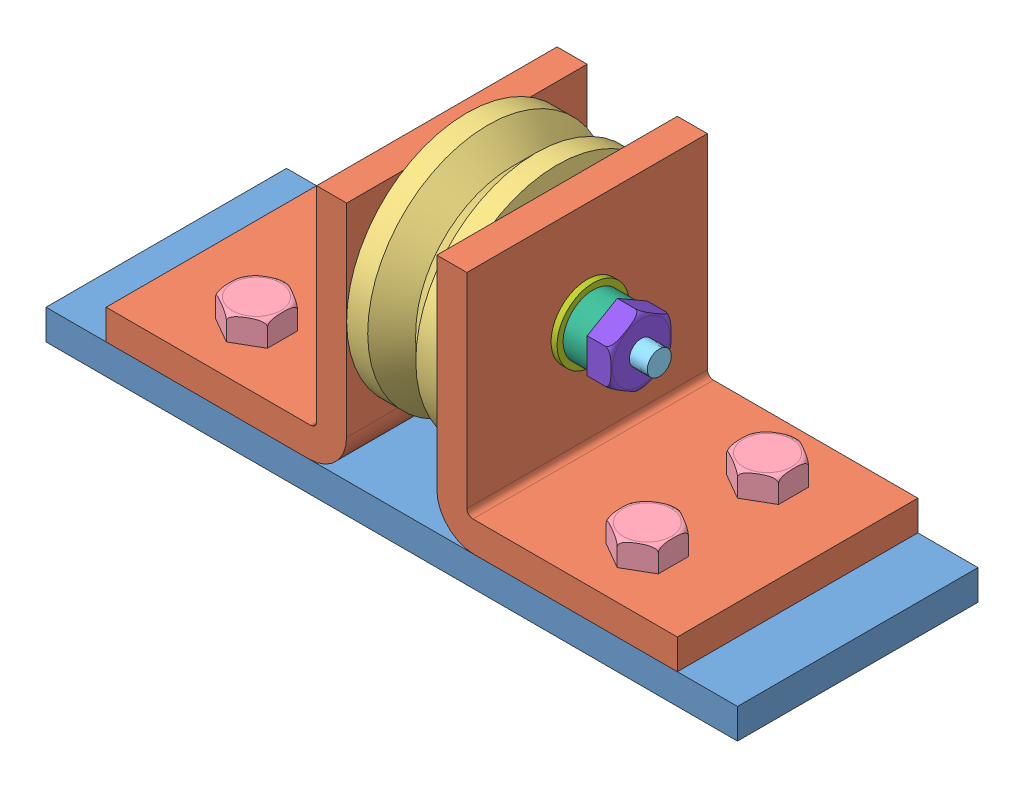
SolidWorks assembly Assem1, configuration Default. Lengths in mm.
Overall size (115 53.85 51.69).
12 component instances, 8 part files, 29 mates.
Components (placement in the parent):
- Part1-1: Part1 [Default] at (31.9592 57.592 95.7045) size (115 5 40)
- Part2-1: Part2 [Default] at (59.4592 62.592 95.7045) size (40 40 40)
- Part3-1: Part3 [Default] at (31.9592 83.092 95.7045) x (1 0 0) z (0 0.358901 -0.933376) size (15 40 40)
- Part8-1: Part8 [Default] at (64.4592 62.592 105.7045) x (-0.868489 0 0.495708) z (-0.495708 0 -0.868489) size (10.5 13.19 9.18)
- Part2-3: Part2 [Default] at (4.4592 62.592 95.7045) x (-1 0 0) z (0 0 -1) size (40 40 40)
- Part4-2: Part4 [Default] at (37.9592 83.092 95.7045) x (-1 0 0) z (0 1 0) size (37 10 10)
- Part6-2: Part6 [Default] at (46.9592 83.092 95.7045) x (0 1 0) z (0 0 -1) size (10 5 10)
- Part7-2: Part7 [Default] at (44.9592 83.092 95.7045) x (0 0.522781 0.852467) z (0 -0.852467 0.522781) size (12 1 12)
- Part5-3: Part5 [Default] at (51.4592 83.092 95.7045) x (0 0 -1) z (1 0 0) size (10.52 12.06 4.35)
- Part8-2: Part8 [Default] at (64.4592 62.592 85.7045) x (-0.863541 0 -0.504279) z (0.504279 0 -0.863541) size (10.5 13.19 9.18)
- Part8-3: Part8 [Default] at (-0.5408 62.592 105.7045) x (-0.868489 0 0.495708) z (-0.495708 0 -0.868489) size (10.5 13.19 9.18)
- Part8-4: Part8 [Default] at (-0.5408 62.592 85.7045) x (-0.868489 0 0.495708) z (-0.495708 0 -0.868489) size (10.5 13.19 9.18)
Mates (geometry in assembly coordinates):
- Concentric1: concentric anti-aligned: cylinder of Part1-1 through (64.4592 60.092 105.7045) axis (0 -1 0) radius 2.5; cylinder of Part2-1 through (64.4592 60.092 105.7045) axis (0 1 0) radius 2.5
- Concentric2: concentric anti-aligned: cylinder of Part1-1 through (64.4592 60.092 85.7045) axis (0 -1 0) radius 2.5; cylinder of Part2-1 through (64.4592 60.092 85.7045) axis (0 1 0) radius 2.5
- Coincident1: coincident anti-aligned: plane of Part1-1 through (31.9592 60.092 95.7045) normal (0 1 0); plane of Part2-1 through (59.4592 60.092 95.7045) normal (0 -1 0)
- Coincident3: coincident anti-aligned: plane of Part2-1 through (59.4592 65.092 95.7045) normal (0 1 0); plane of Part8-1 through (64.4592 65.092 105.7045) normal (0 -1 0)
- Concentric4: concentric aligned: cylinder of Part1-1 through (64.4592 60.092 105.7045) axis (0 -1 0) radius 2.5; cylinder of Part8-1 through (64.4592 65.092 105.7045) axis (0 -1 0) radius 2.5
- Concentric6: concentric: cylinder of Part1-1 through (-0.5408 60.092 105.7045) axis (0 -1 0) radius 2.5; cylinder of Part2-3 through (-0.5408 60.092 105.7045) axis (0 1 0) radius 2.5
- Coincident4: coincident anti-aligned: plane of Part1-1 through (31.9592 60.092 95.7045) normal (0 1 0); plane of Part2-3 through (4.4592 60.092 95.7045) normal (0 -1 0)
- Concentric7: concentric anti-aligned: cylinder of Part2-1 through (39.4592 83.092 95.7045) axis (1 0 0) radius 5; cylinder of Part3-1 through (24.4592 83.092 95.7045) axis (-1 0 0) radius 3.125
- Coincident5: coincident: plane of Part2-1 through (39.4592 65.092 115.7045) normal (-1 0 0); circle of Part3-1
- Coincident6: coincident anti-aligned: circle of Part3-1; cylinder of Part4-2 through (56.4592 83.092 95.7045) axis (1 0 0) radius 3.125
- Coincident7: coincident: plane of Part2-3 through (19.4592 100.092 75.7045) normal (-1 0 0); plane of Part4-2 through (19.4592 83.092 95.7045) normal (-1 0 0)
- Coincident8: coincident anti-aligned: circle of Part2-1; plane of Part6-2 through (44.4592 83.092 95.7045) normal (-1 0 0)
- Coincident16: coincident: cylinder of Part4-2 through (56.4592 83.092 95.7045) axis (1 0 0) radius 3.125; circle of Part7-2
- Concentric10: concentric anti-aligned: circle of Part2-1; circle of Part7-2
- Coincident17: coincident: cylinder of Part4-2 through (56.4592 83.092 95.7045) axis (1 0 0) radius 3.125; circle of Part7-2
- Coincident18: coincident anti-aligned: plane of Part2-1 through (44.4592 100.092 115.7045) normal (1 0 0); plane of Part7-2 through (44.4592 83.092 95.7045) normal (-1 0 0)
- Coincident19: coincident aligned: cylinder of Part4-2 through (56.4592 83.092 95.7045) axis (1 0 0) radius 3.125; circle of Part6-2
- Coincident20: coincident anti-aligned: plane of Part6-2 through (49.4592 83.092 95.7045) normal (1 0 0); plane of Part5-3 through (49.4592 83.092 95.7045) normal (-1 0 0)
- Coincident21: coincident: circle of Part4-2; cylinder of Part5-3 through (43.4592 83.092 95.7045) axis (1 0 0) radius 2
- Parallel2: parallel aligned: plane of Part2-1 through (79.4592 65.092 115.7045) normal (1 0 0); plane of Part8-1 through (68.7894 65.092 105.7045) normal (1 0 0)
- Concentric11: concentric anti-aligned: cylinder of Part2-1 through (64.4592 60.092 85.7045) axis (0 1 0) radius 2.5; cylinder of Part8-2 through (64.4592 65.092 85.7045) axis (0 -1 0) radius 2.5
- Concentric13: concentric: cylinder of Part2-3 through (-0.5408 60.092 105.7045) axis (0 1 0) radius 2.5; cylinder of Part8-3 through (-0.5408 65.092 105.7045) axis (0 -1 0) radius 2.5
- Concentric15: concentric anti-aligned: cylinder of Part2-3 through (-0.5408 60.092 85.7045) axis (0 1 0) radius 2.5; cylinder of Part8-4 through (-0.5408 65.092 85.7045) axis (0 -1 0) radius 2.5
- Coincident24: coincident anti-aligned: plane of Part2-1 through (59.4592 65.092 95.7045) normal (0 1 0); plane of Part8-2 through (64.4592 65.092 85.7045) normal (0 -1 0)
- Coincident25: coincident anti-aligned: plane of Part2-3 through (4.4592 65.092 95.7045) normal (0 1 0); plane of Part8-4 through (-0.5408 65.092 85.7045) normal (0 -1 0)
- Coincident26: coincident: plane of Part2-3 through (4.4592 65.092 95.7045) normal (0 1 0); plane of Part8-3 through (-0.5408 65.092 105.7045) normal (0 -1 0)
- Parallel3: parallel aligned: plane of Part2-1 through (79.4592 65.092 115.7045) normal (1 0 0); plane of Part8-2 through (68.7894 65.092 85.7045) normal (1 0 0)
- Parallel4: parallel aligned: plane of Part2-3 through (-15.5408 65.092 75.7045) normal (-1 0 0); plane of Part8-4 through (-4.8709 65.092 85.7045) normal (-1 0 0)
- Parallel5: parallel aligned: plane of Part2-3 through (-15.5408 65.092 75.7045) normal (-1 0 0); plane of Part8-3 through (-4.8709 65.092 105.7045) normal (-1 0 0)
